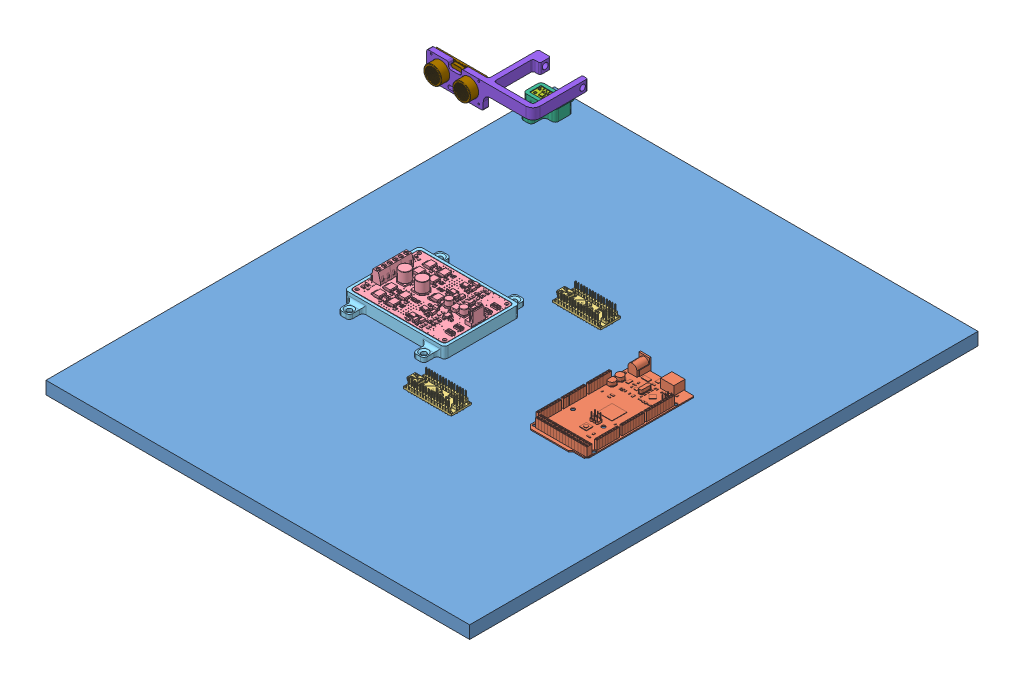
SolidWorks assembly assem_controls, configuration Default. Lengths in mm.
Overall size (381 143.05 457.2).
10 component instances, 9 part files, 26 mates.
Components (placement in the parent):
- controlsPlatform-1: controlsPlatform [Default] at (243.4798 251.1001 501.1556) size (381 11.46 457.2)
- arduinoMega_Elegoo-1: arduinoMega_Elegoo [Default] at (331.5384 262.5555 500.6116) x (0 0 -1) z (1 0 0) size (100 11.65 51.63)
- arduinoNano_Elegoo-1: arduinoNano_Elegoo [Default] at (261.2598 264.3555 426.3356) x (-1 0 0) z (0 0 -1) size (45 11.95 18)
- arduinoNano_Elegoo-2: arduinoNano_Elegoo [Default] at (261.2598 264.3555 560.7356) x (-1 0 0) z (0 0 -1) size (45 11.95 18)
- motorController_Cytron-1: motorController_Cytron [Default] at (129.1798 271.0555 552.3366) x (1 0 0) z (0 1 0) size (84.58 61.72 14.9)
- motorDriverMount-1: motorDriverMount [Default] at (126.4708 262.5555 534.9056) size (90 10 91.5)
- compassMount-1: compassMount [Default] at (52.9798 262.5555 300.7556) size (28.9 10 40.2)
- compassIC_LSM303D-1: compassIC_LSM303D [Default] at (55.9398 271.0555 287.6356) x (0 0 1) z (0 1 0) size (10.16 22.86 2.22)
- ultrasonicSensorMount-1: ultrasonicSensorMount [Default] at (123.1292 374.6068 427.3136) size (95.5 22.86 49.44)
- ultrasonicSensor_hc-sr04-1: ultrasonicSensor_hc-sr04 [Predeterminado] at (123.1292 383.4768 427.3136) size (45.42 26.14 17.7)
Mates (geometry in assembly coordinates):
- Coincident1: coincident: plane of controlsPlatform-1 through (243.4798 262.5555 501.1556) normal (0 1 0); plane of arduinoNano_Elegoo-1 through (255.0348 262.5555 431.0856) normal (0 -1 0)
- Coincident2: coincident: plane of controlsPlatform-1 through (243.4798 262.5555 501.1556) normal (0 1 0); plane of arduinoNano_Elegoo-2 through (255.0348 262.5555 565.4856) normal (0 -1 0)
- Coincident4: coincident: plane of controlsPlatform-1 through (243.4798 262.5555 501.1556) normal (0 1 0); plane of arduinoMega_Elegoo-1 through (331.5384 262.5555 500.6116) normal (0 -1 0)
- Parallel1: parallel: plane of controlsPlatform-1 through (52.9798 262.5555 272.5556) normal (-1 0 0); plane of arduinoMega_Elegoo-1 through (306.1471 253.5555 450.6116) normal (-1 0 0)
- Width1: width: plane of controlsPlatform-1 through (52.9798 262.5555 729.7556) normal (0 0 1); plane of controlsPlatform-1 through (52.9798 262.5555 272.5556) normal (0 0 -1); plane of arduinoMega_Elegoo-1 through (358.0384 263.5555 550.6116) normal (0 0 1); plane of arduinoMega_Elegoo-1 through (318.1504 253.5555 451.6996) normal (0 0 -1)
- Distance1: distance = 76.2 mm: plane of controlsPlatform-1 through (433.9798 262.5555 272.5556) normal (1 0 0); plane of arduinoMega_Elegoo-1 through (357.7798 253.5555 452.1362) normal (1 0 0)
- Width2: width: plane of motorController_Cytron-1 through (132.1008 271.0555 532.0166) normal (0 0 1); plane of motorController_Cytron-1 through (210.8408 271.0555 470.2946) normal (0 0 -1); plane of controlsPlatform-1 through (52.9798 262.5555 729.7556) normal (0 0 1); plane of controlsPlatform-1 through (52.9798 262.5555 272.5556) normal (0 0 -1)
- Distance2: distance = 76.2 mm: plane of controlsPlatform-1 through (52.9798 262.5555 272.5556) normal (-1 0 0); plane of motorController_Cytron-1 through (129.1798 271.0555 473.2156) normal (-1 0 0)
- Parallel2: parallel: plane of controlsPlatform-1 through (52.9798 262.5555 729.7556) normal (0 0 1); plane of arduinoNano_Elegoo-2 through (265.0798 264.3555 577.3556) normal (0 0 1)
- Parallel3: parallel: plane of controlsPlatform-1 through (52.9798 262.5555 272.5556) normal (0 0 -1); plane of arduinoNano_Elegoo-1 through (221.8798 264.3555 424.9556) normal (0 0 -1)
- Width3: width: plane of controlsPlatform-1 through (52.9798 262.5555 272.5556) normal (-1 0 0); plane of controlsPlatform-1 through (433.9798 262.5555 272.5556) normal (1 0 0); plane of arduinoNano_Elegoo-1 through (221.8798 264.3555 442.9556) normal (-1 0 0); plane of arduinoNano_Elegoo-1 through (265.0798 264.3555 424.9556) normal (1 0 0)
- Width4: width: plane of controlsPlatform-1 through (52.9798 262.5555 272.5556) normal (-1 0 0); plane of controlsPlatform-1 through (433.9798 262.5555 272.5556) normal (1 0 0); plane of arduinoNano_Elegoo-2 through (221.8798 264.3555 577.3556) normal (-1 0 0); plane of arduinoNano_Elegoo-2 through (265.0798 264.3555 559.3556) normal (1 0 0)
- Width5: width: plane of controlsPlatform-1 through (52.9798 262.5555 729.7556) normal (0 0 1); plane of controlsPlatform-1 through (52.9798 262.5555 272.5556) normal (0 0 -1); plane of arduinoNano_Elegoo-1 through (221.8798 264.3555 424.9556) normal (0 0 -1); plane of arduinoNano_Elegoo-2 through (265.0798 264.3555 577.3556) normal (0 0 1)
- Distance3: distance = 152.4 mm: plane of controlsPlatform-1 through (52.9798 262.5555 729.7556) normal (0 0 1); plane of arduinoNano_Elegoo-2 through (265.0798 264.3555 577.3556) normal (0 0 1)
- Concentric1: concentric: circle of motorController_Cytron-1; circle of motorDriverMount-1
- Coincident5: coincident: plane of motorController_Cytron-1 through (132.1008 271.0555 532.0166) normal (0 -1 0); plane of motorDriverMount-1 through (126.4708 271.0555 534.9056) normal (0 1 0)
- Coincident6: coincident: plane of controlsPlatform-1 through (243.4798 262.5555 501.1556) normal (0 1 0); plane of motorDriverMount-1 through (126.4708 262.5555 534.9056) normal (0 -1 0)
- Concentric2: concentric: circle of motorController_Cytron-1; circle of motorDriverMount-1
- Coincident7: coincident: plane of controlsPlatform-1 through (243.4798 262.5555 501.1556) normal (0 1 0); plane of compassMount-1 through (52.9798 262.5555 300.7556) normal (0 -1 0)
- Coincident8: coincident: plane of controlsPlatform-1 through (52.9798 262.5555 272.5556) normal (-1 0 0); plane of compassMount-1 through (52.9798 272.5555 284.5556) normal (-1 0 0)
- Coincident9: coincident: plane of controlsPlatform-1 through (52.9798 262.5555 272.5556) normal (0 0 -1); plane of compassMount-1 through (81.8798 262.5555 272.5556) normal (0 0 -1)
- Concentric3: concentric: circle of compassMount-1; circle of compassIC_LSM303D-1
- Parallel4: parallel: plane of compassMount-1 through (78.8798 272.5555 287.5556) normal (0 0 1); plane of compassIC_LSM303D-1 through (78.7998 272.0715 287.6356) normal (0 0 -1)
- Coincident11: coincident: plane of compassMount-1 through (52.9798 271.0555 300.7556) normal (0 1 0); plane of compassIC_LSM303D-1 through (55.9398 271.0555 287.6356) normal (0 -1 0)
- Concentric4: concentric: cylinder of ultrasonicSensorMount-1 through (110.1292 383.4768 432.0761) axis (0 0 -1) radius 8.255; cylinder of ultrasonicSensor_hc-sr04-1 through (110.1292 383.4768 439.3136) axis (0 0 -1) radius 8
- Coincident12: coincident: plane of ultrasonicSensorMount-1 through (126.5582 391.1379 427.3136) normal (0 0 -1); plane of ultrasonicSensor_hc-sr04-1 through (123.1292 383.4768 427.3136) normal (0 0 1)
